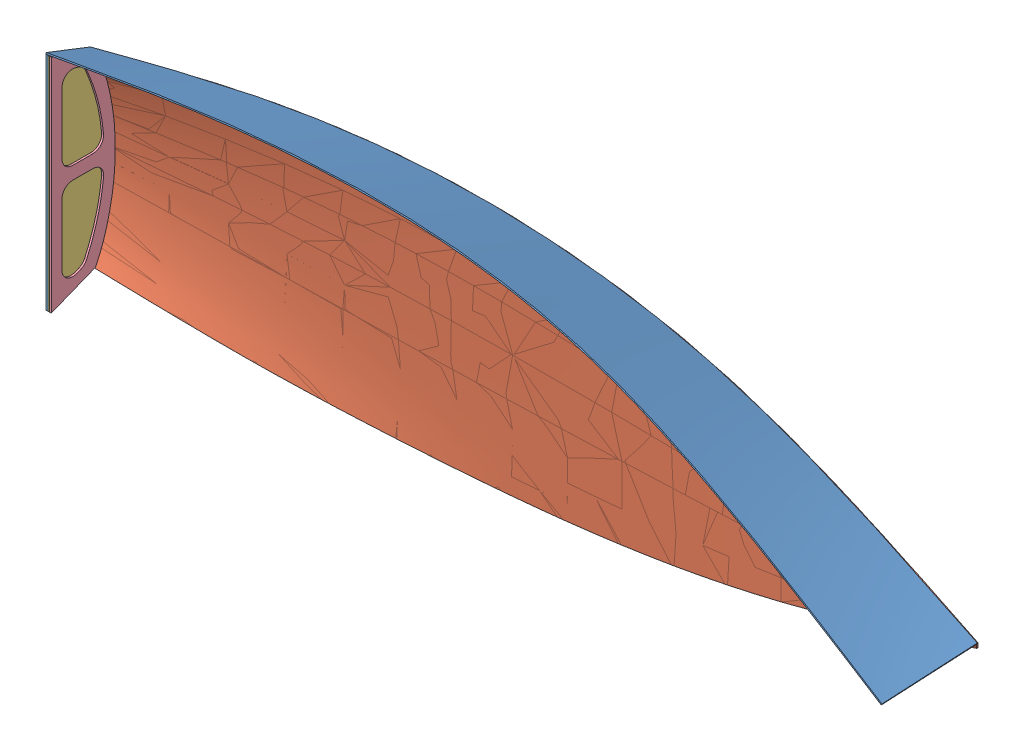
SolidWorks assembly assembly_001, configuration По умолчанию. Lengths in mm.
Overall size (4342.56 1328.66 742.34).
5 component instances, 5 part files, 4 mates.
Components (placement in the parent):
- board_outer_left-2: board_outer_left [По умолчанию] at (787.5526 2350.6323 2542.7992) size (4095.24 745.99 595.47)
- main_deck-1: main_deck [По умолчанию] at (787.5947 2349.8422 2545.1966) size (4342.56 1155.67 403.42)
- transom_central-1: transom_central [По умолчанию] at (797.7289 2351.4351 2544.531) size (6 1033.1 297.33)
- transom_inner-1: transom_inner [По умолчанию] at (803.7289 2351.4351 2544.531) size (9 1033.1 297.33)
- transom_outer-1: transom_outer [По умолчанию] at (788.7289 2351.4351 2544.531) size (9 1033.1 297.33)
Mates (geometry in assembly coordinates):
- Совпадение2: coincident: point of main_deck-1; point of transom_outer-1
- Совпадение3: coincident: point of transom_central-1; point of transom_outer-1
- Совпадение4: coincident: point of transom_central-1; point of transom_inner-1
- Совпадение5: coincident: point of board_outer_left-2; point of main_deck-1
